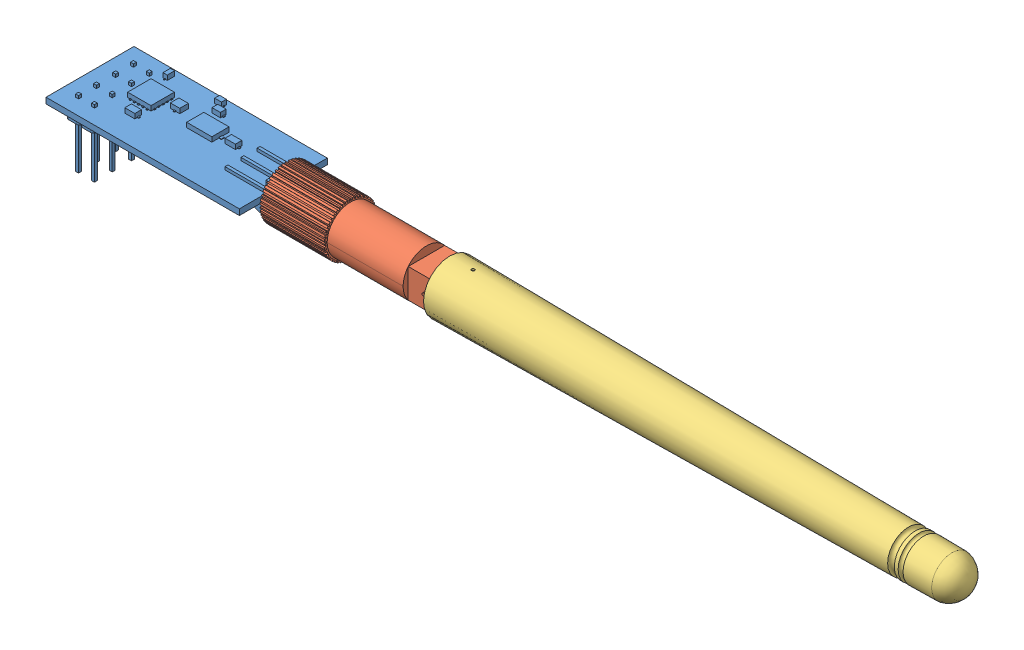
SolidWorks assembly nrf24l01_corrigido, configuration Valor predeterminado. Lengths in mm.
Overall size (150.61 14.5 15.06).
5 component instances, 4 part files, 2 mates.
Components (placement in the parent):
- nrf24l01.STEP-1: nrf24l01.STEP [Valor predeterminado] at origin size (65.11 95 15.06)
  - RFID.STEP-1: RFID.STEP [Valor predeterminado] at (11.1714 22.0988 35.2967) size (42.61 13 15.06)
  - antena bawah.STEP-1: antena bawah.STEP [Valor predeterminado] at (36.2258 22.0988 35.2967) x (0 0 1) z (-1 0 0) size (9 9 28)
  - antena atas.STEP-1: antena atas.STEP [Valor predeterminado] at (55.1123 104.0953 35.3742) x (0 0 1) z (-0.999999 -0.001385 0) size (9 89 8.91) (hidden)
- Antena-1: Antena [Valor predeterminado] at (142.2258 22.0988 35.2967) x (0 -1 0) z (0 0 1) size (9 89 9)
Mates (geometry in assembly coordinates):
- Coincidente1: coincident: plane of nrf24l01.STEP-1/antena bawah.STEP-1 through (56.2258 22.0988 35.2967) normal (1 0 0); plane of Antena-1 through (56.2258 17.5988 35.2967) normal (-1 0 0)
- Concêntrico1: concentric anti-aligned: cylinder of nrf24l01.STEP-1/antena bawah.STEP-1 through (24.8567 22.0988 35.2967) axis (-1 0 0) radius 4; cone of Antena-1 through (134.7813 22.0988 35.2967) axis (1 0 0)
